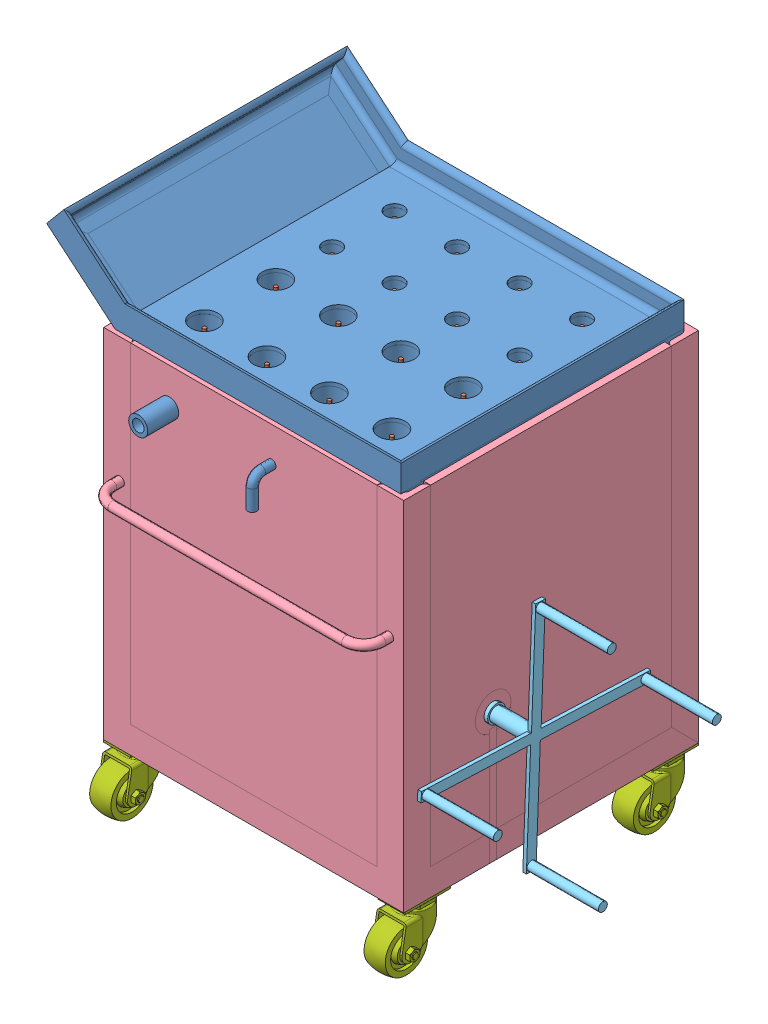
SolidWorks assembly candle making machine, configuration Default. Lengths in mm.
Overall size (266.28 276.97 192.66).
10 component instances, 7 part files, 24 mates.
Components (placement in the parent):
- Mould box-1: Mould box [Default<As Machined>] at (59.0379 15.624 39.6751) x (-1 0 0) z (0 0 -1) size (198.3 92.63 192.66)
- Wick pin assembly-2: Wick pin assembly [Default] at (-24.9225 -42.7123 119.1872) x (-1 0 0) z (0 0 -1) size (139.89 159 142.97)
- rack spur rectangular_ai-1: rack spur rectangular_ai [Inch - Rack-spur - rectangular 16DP 20PA 0.29FW 0.3PH 2.68L---SAll] at (-21.1536 -143.7843 122.3869) x (0 1 0) z (1 0 0) size (68.07 9.21 7.37)
- Frame support-2: Frame support [Default<As Machined>] at (-24.3664 -184.376 114.9416) size (168 200 181.73)
- manual control-1: manual control [Default] at (-19.9873 -111.7715 150.6499) x (1 0 0) z (0 0.039049 0.999237) size (232 128.49 128.49)
- spur gear_am-2: spur gear_am [Metric - Spur gear 2.5M 16T 20PA 6FW ---S16N75H50L10N] at (-28.3399 -111.7715 150.6499) x (1 0 0) z (0 -0.970918 0.239414) size (6 44.35 44.35)
- Roller-1: Roller [2358T51] at (-97.4466 -205.0135 198.2687) size (21.86 33.34 35.72)
- Roller-2: Roller [2358T51] at (-97.4466 -205.0135 58.6687) size (21.86 33.34 35.72)
- Roller-3: Roller [2358T51] at (55.4721 -205.0135 197.5677) size (21.86 33.34 35.72)
- Roller-4: Roller [2358T51] at (55.4721 -205.0135 58.6687) size (21.86 33.34 35.72)
Mates (geometry in assembly coordinates):
- Concentric2: concentric anti-aligned: circle of Mould box-1; circle of Wick pin assembly-2
- Concentric3: concentric anti-aligned: circle of Mould box-1; circle of Wick pin assembly-2
- Coincident3: coincident aligned: line of Wick pin assembly-2 through (-28.5196 -143.7123 122.3869) axis (0 1 0); line of rack spur rectangular_ai-1 through (-28.5196 -143.7843 122.3869) axis (0 1 0)
- Coincident4: coincident anti-aligned: plane of Wick pin assembly-2 through (-24.9225 -75.7123 119.1872) normal (0 -1 0); plane of rack spur rectangular_ai-1 through (-28.5196 -75.7123 122.3869) normal (0 1 0)
- Coincident6: coincident anti-aligned: plane of Wick pin assembly-2 through (-21.3253 -143.7123 122.3869) normal (0 0 1); plane of rack spur rectangular_ai-1 through (-28.5196 -143.7843 122.3869) normal (0 0 -1)
- Parallel2: parallel aligned: line of Mould box-1 through (-101.0448 -33.376 198.0204) axis (0 1 0); line of Frame support-2 through (-104.9873 -184.376 200.6499) axis (0 1 0)
- InPlace1: in place: plane of ? through (-96.6564 -12.1431 27.9283) normal (0 1 0); plane of ? through (0 -12.1431 0) normal (0 1 0); moOrthogonalPlaneRef_w of ? through (-96.6564 -12.1431 27.9283) normal (0 1 0); plane of ? through (0 -12.1431 0) normal (0 0 -1); plane of ? through (-96.6564 -12.1431 27.9283) normal (0 1 0); plane of ? through (0 -12.1431 0) normal (1 0 0); plane of Frame support-2 through (-92.9873 15.624 35.6499) normal (0 1 0); unknown of ?
- Coincident12: coincident aligned: plane of Frame support-2; plane of ?
- Coincident13: coincident aligned: moOrthogonalPlaneRef_w of Frame support-2 through (-24.3664 15.624 114.9416) normal (0 0 -1); plane of Part4^candle making machine-1 through (-24.3664 15.624 114.9416) normal (0 0 -1)
- Coincident14: coincident anti-aligned: moOrthogonalPlaneRef_w of Frame support-2 through (-24.3664 15.624 114.9416) normal (-1 0 0); plane of Part4^candle making machine-1 through (-24.3664 15.624 114.9416) normal (1 0 0)
- Coincident15: coincident: point of Mould box-1; moEndPointRef_w of Frame support-2
- Concentric4: concentric aligned: cylinder of Frame support-2 through (-92.9873 -111.7715 150.6499) axis (-1 0 0) radius 5; cylinder of manual control-1 through (65.0127 -111.7715 150.6499) axis (-1 0 0) radius 5
- Coincident17: coincident aligned: plane of Frame support-2 through (-104.9873 -111.7715 150.6499) normal (-1 0 0); plane of manual control-1 through (-104.9873 -111.7715 150.6499) normal (-1 0 0)
- Concentric5: concentric aligned: cylinder of manual control-1 through (65.0127 -111.7715 150.6499) axis (-1 0 0) radius 5; cylinder of spur gear_am-2 through (21.6602 -111.7715 150.6499) axis (-1 0 0) radius 5
- Parallel3: parallel aligned: plane of Wick pin assembly-2 through (-28.5196 -143.7123 122.3869) normal (-1 0 0); plane of spur gear_am-2 through (-28.3399 -111.7715 150.6499) normal (-1 0 0)
- RackPinionMate1: rack pinion = 45 mm: line of rack spur rectangular_ai-1 through (-28.5196 -90.9203 131.5944) axis (0 -1 0); circle of spur gear_am-2
- Concentric6: concentric aligned: cylinder of manual control-1 through (65.0127 -111.7715 150.6499) axis (-1 0 0) radius 5; cylinder of spur gear_am-2 through (21.6602 -111.7715 150.6499) axis (-1 0 0) radius 5
- Coincident18: coincident aligned: line of Frame support-2 through (-104.9873 -184.376 35.6499) axis (0 0 1); line of Roller-1 through (-104.9873 -184.376 175.2499) axis (0 0 1)
- Coincident19: coincident anti-aligned: line of Frame support-2 through (63.0127 -184.376 200.6499) axis (-1 0 0); line of Roller-1 through (-104.9873 -184.376 200.6499) axis (1 0 0)
- Coincident20: coincident aligned: line of Frame support-2 through (-104.9873 -184.376 35.6499) axis (0 0 1); line of Roller-2 through (-104.9873 -184.376 35.6499) axis (0 0 1)
- Coincident21: coincident anti-aligned: line of Frame support-2 through (-104.9873 -184.376 35.6499) axis (1 0 0); line of Roller-2 through (-89.906 -184.376 35.6499) axis (-1 0 0)
- Coincident22: coincident aligned: line of Frame support-2 through (63.0127 -184.376 200.6499) axis (0 0 -1); line of Roller-3 through (63.0127 -184.376 199.9489) axis (0 0 -1)
- Coincident23: coincident aligned: line of Frame support-2 through (63.0127 -184.376 200.6499) axis (0 0 -1); line of Roller-4 through (63.0127 -184.376 61.0499) axis (0 0 -1)
- Coincident24: coincident aligned: line of Frame support-2 through (63.0127 -184.376 35.6499) axis (-1 0 0); line of Roller-4 through (63.0127 -184.376 35.6499) axis (-1 0 0)
